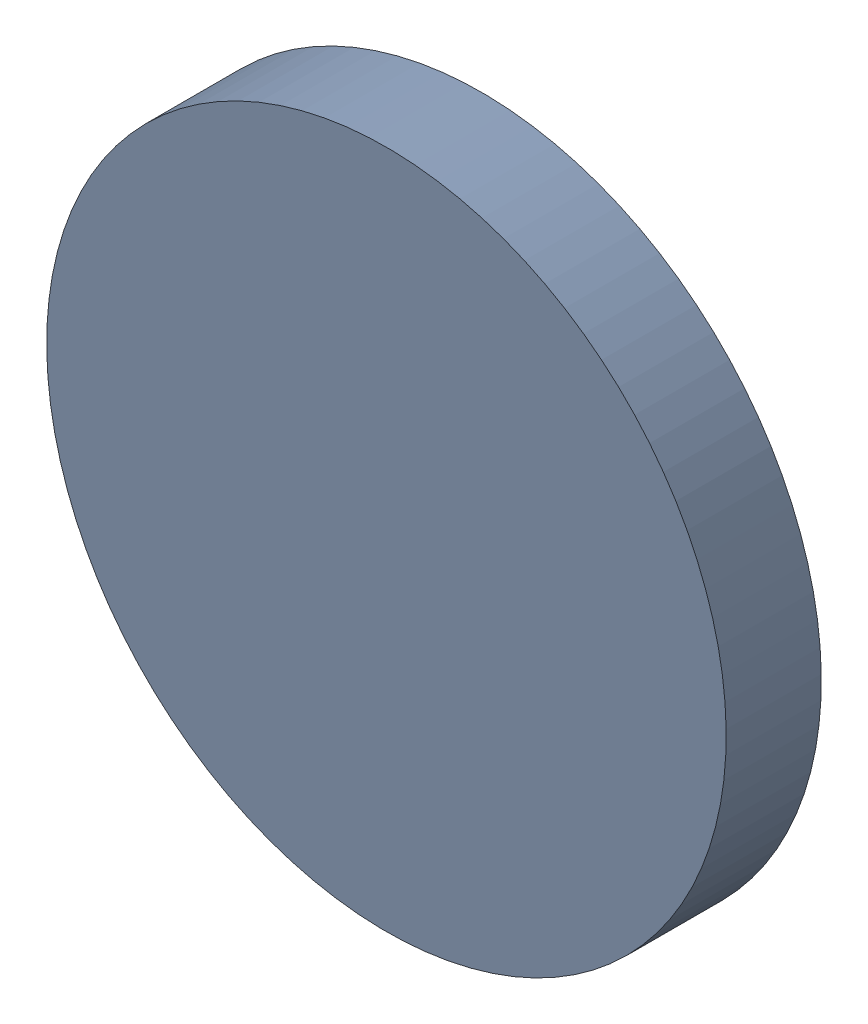
SolidWorks assembly Track (27.8mm,43.5mm)(27.8mm,43.5mm) on Top Layer, configuration Predeterminado. Lengths in mm.
Overall size (0.25 0.25 0.04).
2 component instances, 1 part files, 0 mates.
Components (placement in the parent):
- Track (27.8mm,43.5mm)(27.8mm,43.5mm) on Top Layer-1-1: Track (27.8mm,43.5mm)(27.8mm,43.5mm) on Top Layer-1 [Predeterminado] at (-68.317 -44.187 -0.0457) size (0.25 0.25 0.04)
  - Track (27.8mm,43.5mm)(27.8mm,43.5mm) on Top Layer-Part-1-1: Track (27.8mm,43.5mm)(27.8mm,43.5mm) on Top Layer-Part-1 [Predeterminado] at origin size (0.25 0.25 0.04)
